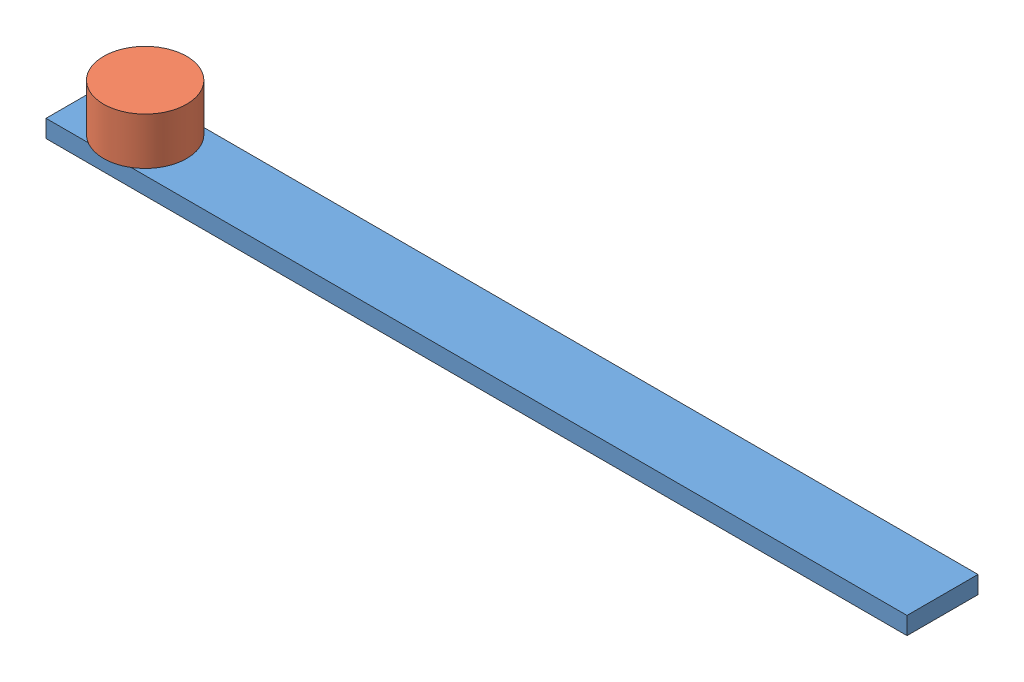
SolidWorks assembly assembly1, configuration Default. Lengths in mm.
Overall size (311 23.34 30).
2 component instances, 2 part files, 6 mates.
Components (placement in the parent):
- link-1: link [Default] at (132.5 -23.34 0) size (311 6.34 25.64)
- pulley-1: pulley [Default] x (1 0 0) z (0 0 -1) size (30 17 30)
Mates (geometry in assembly coordinates):
- Coincident1: coincident anti-aligned: plane of link-1 through (132.5 -17 0) normal (0 1 0); plane of pulley-1 through (0 -17 0) normal (0 -1 0)
- Coincident2: coincident anti-aligned: plane of link-1 through (132.5 -23.34 0) normal (0 0 1); plane of pulley-1 through (0 0 0) normal (0 0 -1)
- Distance1: distance = 23 mm anti-aligned: plane of pulley-1; plane of link-1 through (-23 -17 -12.82) normal (-1 0 0)
- Coincident8: coincident: plane of pulley-1 through (0 0 0) normal (0 1 0); point of assembly
- Coincident9: coincident: plane of pulley-1; point of assembly
- Coincident10: coincident: plane of pulley-1 through (0 0 0) normal (0 0 -1); point of assembly
